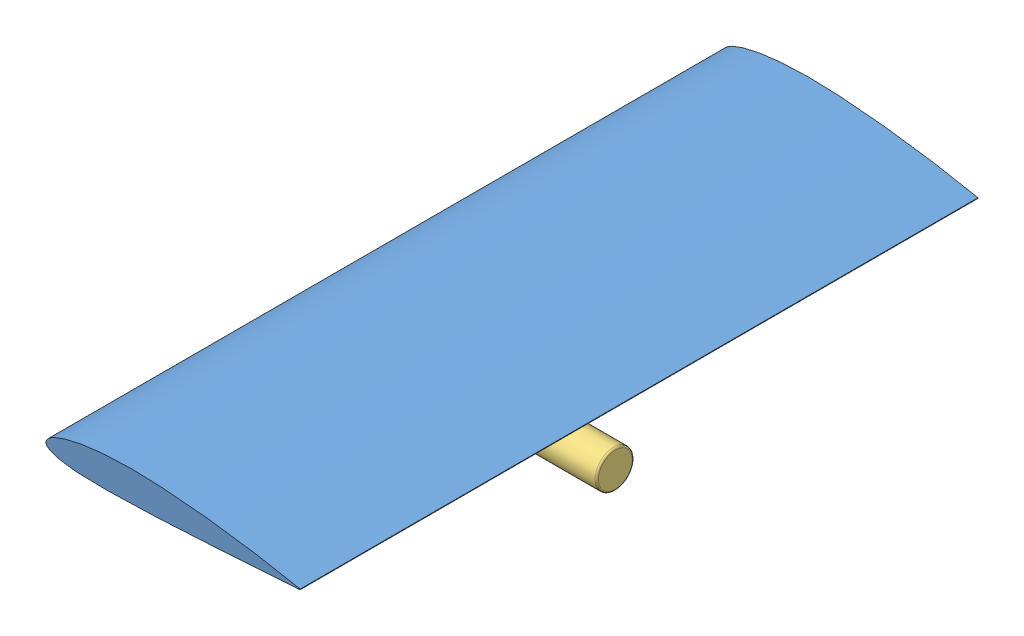
SolidWorks assembly Mont1, configuration Valor predeterminado. Lengths in mm.
Overall size (1690.13 686.46 4000).
3 component instances, 3 part files, 6 mates.
Components (placement in the parent):
- Asa Nova-1: Asa Nova [Valor predeterminado] at (-576.5372 -46.554 4000) size (1500.98 182.65 4000)
- Plataforma de Integração Nova-1: Plataforma de Integração Nova [Valor predeterminado] at (23.4628 -329.0017 4000) x (0 0 1) z (0 1 0) size (362.86 853.04 263.47)
- Lancador Novo-1: Lancador Novo [Valor predeterminado] at (783.4628 -504.0017 4000) x (0 0 1) z (-1 0 0) size (220 285 1550)
Mates (geometry in assembly coordinates):
- Coincidente1: coincident aligned: plane of Asa Nova-1 through (-576.5372 -46.554 4000) normal (0 0 1); plane of Plataforma de Integração Nova-1 through (23.4628 -329.0017 4000) normal (0 0 1)
- Distância1: distance = 600 mm aligned: plane of Asa Nova-1 through (-576.5372 -46.554 4000) normal (1 0 0); plane of Plataforma de Integração Nova-1 through (23.4628 -329.0017 4000) normal (1 0 0)
- Coincidente3: coincident anti-aligned: plane of Plataforma de Integração Nova-1 through (273.4628 -329.0017 4000) normal (0 -1 0); plane of Lancador Novo-1 through (183.4628 -329.0017 4000) normal (0 1 0)
- Coincidente5: coincident aligned: plane of Asa Nova-1 through (-576.5372 -46.554 4000) normal (0 0 1); plane of Lancador Novo-1 through (783.4628 -504.0017 4000) normal (0 0 1)
- Distância2: distance = 760 mm anti-aligned: plane of Lancador Novo-1 through (783.4628 -504.0017 4000) normal (-1 0 0); plane of Plataforma de Integração Nova-1 through (23.4628 -329.0017 4000) normal (1 0 0)
- Distância3: distance = 282.4477 mm anti-aligned: plane of Asa Nova-1 through (-576.5372 -46.554 4000) normal (0 1 0); plane of Plataforma de Integração Nova-1 through (273.4628 -329.0017 4000) normal (0 -1 0)
